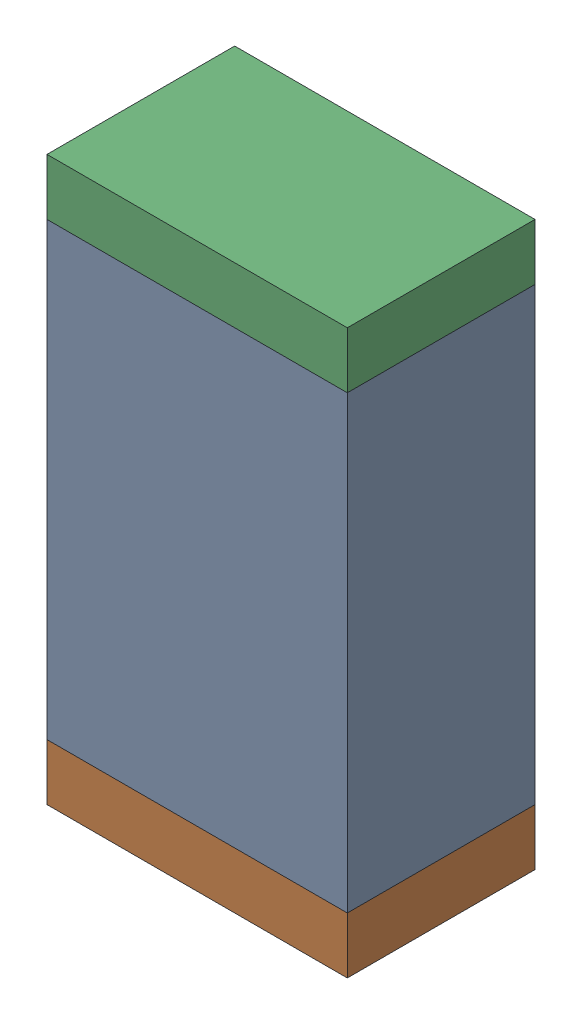
SolidWorks assembly R7, configuration Default. Lengths in mm.
Overall size (0.8 1.5 0.5).
6 component instances, 2 part files, 0 mates.
Components (placement in the parent):
- 810156976-1: 810156976 [Default] at (128.35 33.15 0) size (0.8 1.2 0.5)
  - Extruded_6-1: Extruded_6 [Default] at origin size (0.8 1.2 0.5)
- 810156592-1: 810156592 [Default] at (128.35 32.475 0) size (0.8 0.15 0.5)
  - Extruded_7-1: Extruded_7 [Default] at origin size (0.8 0.15 0.5)
- 810156592-2: 810156592 [Default] at (128.35 33.825 0) size (0.8 0.15 0.5)
  - Extruded_7-1: Extruded_7 [Default] at origin size (0.8 0.15 0.5)
